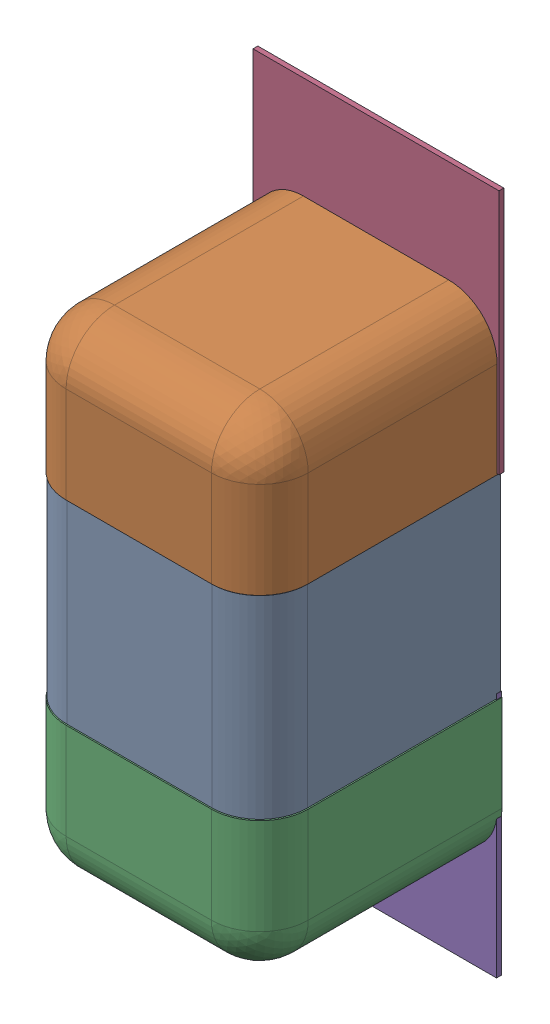
SolidWorks assembly C75, configuration Défaut. Lengths in mm.
Overall size (0.51 1.41 0.5).
8 component instances, 4 part files, 0 mates.
Components (placement in the parent):
- 6501210464-1: 6501210464 [Défaut] at (17.6629 -22.0508 0) x (0 -1 0) z (-1 0 0) size (1 0.5 0.5)
  - Open CASCADE STEP translator 7.5 2.33.1.1-1: Open CASCADE STEP translator 7.5 2.33.1.1 [Défaut] at origin size (0.4 0.5 0.5)
  - Open CASCADE STEP translator 7.5 2.33.1.2-1: Open CASCADE STEP translator 7.5 2.33.1.2 [Défaut] at origin size (0.3 0.5 0.5)
  - Open CASCADE STEP translator 7.5 2.33.1.3-1: Open CASCADE STEP translator 7.5 2.33.1.3 [Défaut] at origin size (0.3 0.5 0.5)
- 6504207776-1: 6504207776 [Défaut] at (17.6628 -21.5935 0) size (0.51 0.51 0.01)
  - Extruded-1: Extruded [Défaut] at origin size (0.51 0.51 0.01)
- 6504207776-2: 6504207776 [Défaut] at (17.6577 -22.4958 0) size (0.51 0.51 0.01)
  - Extruded-1: Extruded [Défaut] at origin size (0.51 0.51 0.01)
